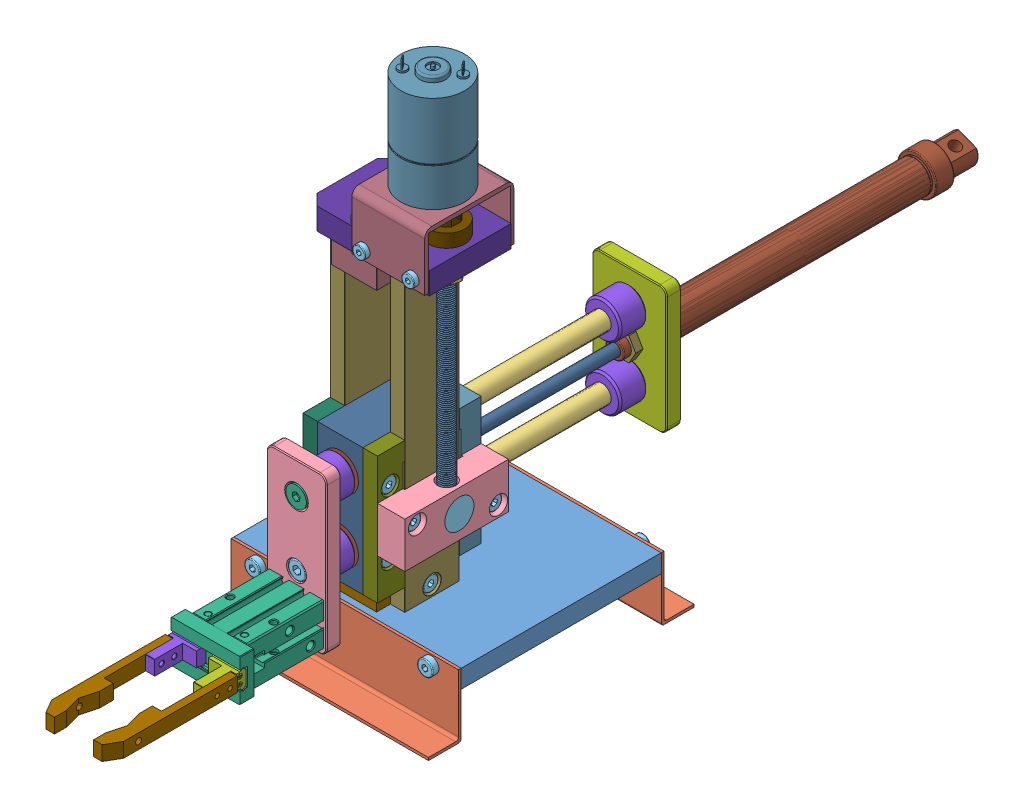
SolidWorks assembly cum_s4, configuration Default. Lengths in mm.
Overall size (125 291 489.3).
72 component instances, 34 part files, 168 mates.
Components (placement in the parent):
- tam_de-1: tam_de [Default] at (55.7373 162.4347 98.3877) size (125 10 110)
- khoi_do-1: khoi_do [Default] at (118.2373 137.4347 153.3877) x (0 0 1) z (0 -1 0) size (18 125 35)
- khoi_do-2: khoi_do [Default] at (-6.7627 137.4347 43.3877) x (0 0 -1) z (0 -1 0) size (18 125 35)
- chot_dan_huong-1: chot_dan_huong [Default] at (55.7373 236.9347 173.4357) x (0.807467 -0.589913 0) z (0.589913 0.807467 0) size (10 175 10)
- chot_dan_huong-2: chot_dan_huong [Default] at (55.7373 201.9347 173.4357) x (0.458763 0.888559 0) z (-0.888559 0.458763 0) size (10 175 10)
- ban_canh_truoc-1: ban_canh_truoc [Default] at (55.7373 211.4347 173.4357) x (1 0 0) z (0 -1 0) size (33 8 86)
- socket head thin cap screw_din-14: socket head thin cap screw_din [DIN 7984 - M5 x 8 --- 5.6N] at (8.2373 167.4347 38.3877) x (0 0 1) z (-1 0 0) size (11.5 8.5 8.5)
- socket head thin cap screw_din-16: socket head thin cap screw_din [DIN 7984 - M5 x 8 --- 5.6N] at (8.2373 167.4347 158.3877) x (0 0 -1) z (1 0 0) size (11.5 8.5 8.5)
- socket head thin cap screw_din-17: socket head thin cap screw_din [DIN 7984 - M5 x 8 --- 5.6N] at (103.2373 167.4347 158.3877) x (0 0 -1) z (1 0 0) size (11.5 8.5 8.5)
- socket head thin cap screw_din-18: socket head thin cap screw_din [DIN 7984 - M5 x 8 --- 5.6N] at (63.2373 164.6347 109.3877) x (0 1 0) z (0 0 1) size (11.5 8.5 8.5)
- socket head thin cap screw_din-19: socket head thin cap screw_din [DIN 7984 - M5 x 8 --- 5.6N] at (48.2373 164.6347 145.3877) x (0 1 0) z (0 0 1) size (11.5 8.5 8.5)
- socket head thin cap screw_din-22: socket head thin cap screw_din [DIN 7984 - M5 x 8 --- 5.6N] at (103.2373 167.4347 38.3877) x (0 0 1) z (-1 0 0) size (11.5 8.5 8.5)
- socket head thin cap screw_din-23: socket head thin cap screw_din [DIN 7984 - M6 x 10 --- 7N] at (55.7373 201.9347 -9.3643) x (0 0 1) z (-1 0 0) size (14 10 10)
- socket head thin cap screw_din-24: socket head thin cap screw_din [DIN 7984 - M6 x 10 --- 7N] at (55.7373 201.6984 181.2357) x (0 0 -1) z (1 0 0) size (14 10 10)
- socket csink head cap screw 10642_din-2: socket csink head cap screw 10642_din [EN ISO 10642 - M6 x 8 - 8N] at (55.7373 236.9347 -9.7843) x (0 0 1) z (-0.997818 -0.066017 0) size (8 11.34 11.34)
- socket csink head cap screw 10642_din-3: socket csink head cap screw 10642_din [EN ISO 10642 - M6 x 8 - 8N] at (55.7373 236.9347 181.6557) x (0 0 -1) z (0.99607 -0.088565 0) size (8 11.34 11.34)
- s3_ban_canh_sau-1: s3_ban_canh_sau [Default] at (55.7373 219.4347 -1.5643) x (-1 0 0) z (0 -1 0) size (41 8 70)
- bac_chan-1: bac_chan [Default] at (55.7373 236.9347 158.4357) x (-0.999622 -0.027501 0) z (-0.027501 0.999622 0) size (20 15 20)
- bac_chan-2: bac_chan [Default] at (55.7373 201.9347 158.4357) x (1 0 0) z (0 -1 0) size (20 15 20)
- bac_chan-3: bac_chan [Default] at (55.7373 236.9347 13.4357) x (-0.997429 -0.071658 0) z (0.071658 -0.997429 0) size (20 15 20)
- bac_chan-4: bac_chan [Default] at (55.7373 201.9347 13.4357) x (1 0 0) z (0 1 0) size (20 15 20)
- mieng_dem_duoi-1: mieng_dem_duoi [Default] at (55.7373 172.4347 127.3877) size (25 12 45)
- con_truot_s4_as-1: con_truot_s4_as [Default] at (19.8229 164.1862 110.8419) x (0 0 1) z (0 1 0) size (45 28.02 70)
  - con_truot_s4-1: con_truot_s4 [Default] at (24.0458 23.4144 55.2485) size (45 25 70)
  - bat_lot-1: bat_lot [Default] at (46.5458 35.9144 72.7485) x (0 0.967524 -0.252781) z (0 0.252781 0.967524) size (20 10 20)
  - bat_lot-2: bat_lot [Default] at (46.5458 35.9144 37.7485) x (0 0.967524 -0.252781) z (0 0.252781 0.967524) size (20 10 20)
  - bat_lot-3: bat_lot [Default] at (1.5458 35.9144 72.7485) x (0 0.603074 -0.797685) z (0 -0.797685 -0.603074) size (20 10 20)
  - bat_lot-4: bat_lot [Default] at (1.5458 35.9144 37.7485) x (0 0.603074 -0.797685) z (0 -0.797685 -0.603074) size (20 10 20)
- thanh_dan_huong_lon-1: thanh_dan_huong_lon [Default] at (68.2373 254.9347 127.3877) x (0 0 -1) z (0 -1 0) size (30 8 165)
- thanh_dan_huong_lon-2: thanh_dan_huong_lon [Default] at (43.2373 254.9347 127.3877) x (0 0 -1) z (0 1 0) size (30 8 165)
- mieng_dem_tren-1: mieng_dem_tren [Default] at (55.7373 325.4347 127.3877) size (25 12 45)
- tam_dan_huong-1: tam_dan_huong [Default] at (35.2373 219.4347 106.3877) x (0 0 -1) z (0 -1 0) size (12 41 70)
- thanh_dan_huong_nho_1-1: thanh_dan_huong_nho_1 [Default] at (43.2373 219.4347 149.8877) x (0 0 -1) z (0 1 0) size (15 8 70)
- thanh_dan_huong_nho_2-1: thanh_dan_huong_nho_2 [Default] at (68.2373 219.4347 149.8877) x (0 0 -1) z (0 -1 0) size (15 8 70)
- tam_de_s5-1: tam_de_s5 [Default] at (63.3484 349.4347 127.3877) x (0 0 1) z (1 0 0) size (45 12 67.78)
- dau_kep_truc_vit-1: dau_kep_truc_vit [Default] at (84.2373 339.6347 127.3877) x (-0.999219 0 -0.039516) z (0.039516 0 -0.999219) size (20 25 20)
- truc_truyen_dong-1: truc_truyen_dong [Default] at (84.2373 208.6347 127.3877) x (-0.676321 0 -0.736607) z (0.736607 0 -0.676321) size (8.27 150.4 9.24)
- vong_dem-1: vong_dem [Default] at (84.2373 337.4347 127.3877) x (-0.77791 0 0.628376) z (-0.628376 0 -0.77791) size (19.6 2 19.6)
- hex nut gradec_din-5: hex nut gradec_din [Hexagon Nut ISO 4034 - M8 - N] at (84.2373 329.5347 127.3877) x (0.78301 0 -0.622008) z (0 -1 0) size (13 15.01 7.9)
- thanh_ngang-1: thanh_ngang [Default] at (83.7373 206.9347 128.8877) x (0 0 -1) z (1 0 0) size (57 25 15)
- dai_oc-1: dai_oc [Default] at (77.2373 219.4347 127.3877) x (0 0.924256 0.381773) z (0 0.381773 -0.924256) size (16 14 16)
- socket head thin cap screw_din-25: socket head thin cap screw_din [DIN 7984 - M5 x 8 --- 5.6N] at (89.0373 212.9347 105.8877) x (-1 0 0) z (0 0.924225 0.381849) size (11.5 8.5 8.5)
- socket head thin cap screw_din-26: socket head thin cap screw_din [DIN 7984 - M5 x 8 --- 5.6N] at (89.0373 225.9347 150.3877) x (-1 0 0) z (0 0.924225 0.381849) size (11.5 8.5 8.5)
- socket head thin cap screw_din-27: socket head thin cap screw_din [DIN 7984 - M5 x 8 --- 5.6N] at (75.5373 236.9347 150.3877) x (-1 0 0) z (0 0.924225 0.381849) size (11.5 8.5 8.5)
- socket head thin cap screw_din-28: socket head thin cap screw_din [DIN 7984 - M5 x 8 --- 5.6N] at (75.5373 201.9347 150.3877) x (-1 0 0) z (0 0.924225 0.381849) size (11.5 8.5 8.5)
- socket head thin cap screw_din-29: socket head thin cap screw_din [DIN 7984 - M5 x 8 --- 5.6N] at (75.5373 178.4347 127.3877) x (-1 0 0) z (0 0.924225 0.381849) size (11.5 8.5 8.5)
- socket head thin cap screw_din-30: socket head thin cap screw_din [DIN 7984 - M5 x 8 --- 5.6N] at (35.9373 178.4347 127.3877) size (11.5 8.5 8.5)
- socket head thin cap screw_din-31: socket head thin cap screw_din [DIN 7984 - M5 x 8 --- 5.6N] at (35.9373 201.9347 150.3877) size (11.5 8.5 8.5)
- socket head thin cap screw_din-32: socket head thin cap screw_din [DIN 7984 - M5 x 8 --- 5.6N] at (35.9373 236.9347 150.3877) size (11.5 8.5 8.5)
- socket head thin cap screw_din-33: socket head thin cap screw_din [DIN 7984 - M5 x 8 --- 5.6N] at (35.9373 331.4347 127.3877) size (11.5 8.5 8.5)
- socket head thin cap screw_din-34: socket head thin cap screw_din [DIN 7984 - M5 x 8 --- 5.6N] at (63.2373 248.4347 102.5877) x (0 0 1) z (-1 0 0) size (11.5 8.5 8.5)
- socket head thin cap screw_din-35: socket head thin cap screw_din [DIN 7984 - M5 x 8 --- 5.6N] at (48.2373 190.4347 102.5877) x (0 0 1) z (-1 0 0) size (11.5 8.5 8.5)
- socket head thin cap screw_din-36: socket head thin cap screw_din [DIN 7984 - M5 x 8 --- 5.6N] at (55.7373 352.9347 145.3877) x (0 -1 0) z (0 0 1) size (11.5 8.5 8.5)
- socket head thin cap screw_din-37: socket head thin cap screw_din [DIN 7984 - M5 x 8 --- 5.6N] at (55.7373 352.9347 109.3877) x (0 -1 0) z (0 0 1) size (11.5 8.5 8.5)
- body-2: body [默认] at (55.7373 183.6347 181.4357) x (0 0 -1) z (0 1 0) size (50 38 23.6)
- ljaw-1: ljaw [默认] at (59.0373 183.6347 181.4357) x (0 0 -1) z (0 -1 0) size (21.3 15.4 11.12)
- rjaw-1: rjaw [默认] at (52.4373 183.6347 181.4357) x (0 0 -1) z (0 -1 0) size (21.3 15.6 11.12)
- jaw - ip-1: jaw - ip [Default] at (36.1895 179.6347 269.1328) x (0 0 -1) z (1 0 0) size (70 8 9.03)
- jaw - ip-2: jaw - ip [Default] at (75.2851 187.6347 269.1328) x (0 0 -1) z (-1 0 0) size (70 8 9.03)
- Part1-1: Part1 [Default] at (55.7373 219.4347 -37.6123) x (-0.66535 -0.746532 0) z (-0.746532 0.66535 0) size (6.2 165 6.2)
- 16 X 100 Cylinder bore-1: 16 X 100 Cylinder bore [Default] at (55.7373 219.4347 -89.5643) x (-0.367131 -0.930169 0) z (0 0 -1) size (21.5 21.5 192)
- hex thin nut gradeb_din-1: hex thin nut gradeb_din [Hexagon Nut ISO 4036 - M8 - N] at (55.7373 219.4347 2.4357) x (0.866025 0.5 0) z (0 0 1) size (13 15.01 4)
- de dong co-1: de dong co [Default] at (96.7373 353.9347 127.4836) x (0 0 1) z (0 -1 0) size (49 40 31)
- moto-1: moto [Default] at (76.7373 371.6519 127.4836) x (0 -1 0) z (-1 0 0) size (63.5 35 35)
- link-1: link [Default] at (76.7432 371.6519 127.1872) x (0 -1 0) z (-0.999219 0 -0.039516) size (19 10 10)
- socket head thin cap screw_din-39: socket head thin cap screw_din [DIN 7984 - M4 x 6 --- 3.9N] at (63.2373 343.4347 154.7836) x (0 0 -1) z (1 0 0) size (8.8 7 7)
- socket head thin cap screw_din-40: socket head thin cap screw_din [DIN 7984 - M4 x 6 --- 3.9N] at (90.2373 343.4347 100.1836) x (0 0 1) z (-1 0 0) size (8.8 7 7)
- socket head thin cap screw_din-41: socket head thin cap screw_din [DIN 7984 - M4 x 6 --- 3.9N] at (63.2373 343.4347 100.1836) x (0 0 1) z (-1 0 0) size (8.8 7 7)
- socket head thin cap screw_din-44: socket head thin cap screw_din [DIN 7984 - M4 x 6 --- 3.9N] at (90.2373 343.4347 154.7836) x (0 0 -1) z (1 0 0) size (8.8 7 7)
- slotted headless screw_din-5: slotted headless screw_din [DIN 427 M2 x 5 --- 2.4N] at (91.7315 361.1868 127.6841) x (-0.999219 0 -0.039516) z (0.039508 -0.021253 -0.998993) size (5 2 2)
- socket head thin cap screw_din-45: socket head thin cap screw_din [DIN 7984 - M4 x 10 --- 7.9N] at (66.7373 191.1347 175.0357) x (0 0 1) z (-1 0 0) size (12.8 7 7)
- socket head thin cap screw_din-46: socket head thin cap screw_din [DIN 7984 - M4 x 10 --- 7.9N] at (44.7373 176.1347 175.0357) x (0 0 1) z (-1 0 0) size (12.8 7 7)
Mates (geometry in assembly coordinates):
- Parallel1: parallel aligned: plane of tam_de-1 through (-6.7627 172.4347 153.3877) normal (0 0 1); plane of khoi_do-1 through (-6.7627 172.4347 154.8877) normal (0 0 1)
- Concentric1: concentric aligned: cylinder of tam_de-1 through (8.2373 167.4347 153.3877) axis (0 0 1) radius 2.1; circle of khoi_do-1
- Concentric2: concentric aligned: circle of tam_de-1; circle of khoi_do-1
- Coincident1: coincident anti-aligned: plane of tam_de-1 through (-6.7627 172.4347 153.3877) normal (0 0 1); plane of khoi_do-1 through (-6.7627 137.4347 153.3877) normal (0 0 -1)
- Parallel2: parallel anti-aligned: plane of tam_de-1 through (-6.7627 172.4347 43.3877) normal (0 0 -1); plane of khoi_do-2 through (118.2373 137.4347 43.3877) normal (0 0 1)
- Concentric3: concentric aligned: circle of tam_de-1; cylinder of khoi_do-2 through (8.2373 167.4347 43.3877) axis (0 0 -1) radius 2.75
- Parallel3: parallel aligned: plane of tam_de-1 through (55.7373 172.4347 98.3877) normal (0 1 0); plane of khoi_do-2 through (118.2373 172.4347 43.3877) normal (0 1 0)
- Coincident2: coincident anti-aligned: plane of tam_de-1 through (-6.7627 172.4347 43.3877) normal (0 0 -1); plane of khoi_do-2 through (118.2373 137.4347 43.3877) normal (0 0 1)
- Concentric18: concentric aligned: cylinder of chot_dan_huong-2 through (55.7373 272.9347 260.3877) axis (0 0 1) radius 2.5; circle of ban_canh_truoc-1
- Concentric19: concentric anti-aligned: circle of chot_dan_huong-1; circle of ban_canh_truoc-1
- Coincident14: coincident aligned: plane of chot_dan_huong-1 through (55.7373 307.9347 260.3877) normal (0 0 1); circle of ban_canh_truoc-1
- Coincident15: coincident aligned: circle of chot_dan_huong-2; plane of ban_canh_truoc-1 through (55.7373 282.4347 260.3877) normal (0 0 -1)
- Concentric37: concentric aligned: cylinder of khoi_do-2 through (8.2373 167.4347 43.3877) axis (0 0 -1) radius 2.75; cylinder of socket head thin cap screw_din-14 through (8.2373 167.4347 6.6377) axis (0 0 -1) radius 4.25
- Coincident28: coincident anti-aligned: plane of khoi_do-2 through (118.2373 172.4347 41.8877) normal (0 0 -1); plane of socket head thin cap screw_din-14 through (8.2373 171.6847 41.8877) normal (0 0 1)
- Concentric39: concentric aligned: cylinder of khoi_do-1 through (8.2373 167.4347 153.3877) axis (0 0 1) radius 2.75; cylinder of socket head thin cap screw_din-16 through (8.2373 167.4347 190.1377) axis (0 0 1) radius 4.25
- Coincident30: coincident anti-aligned: plane of khoi_do-1 through (-6.7627 172.4347 154.8877) normal (0 0 1); plane of socket head thin cap screw_din-16 through (8.2373 171.6847 154.8877) normal (0 0 -1)
- Concentric40: concentric aligned: cylinder of khoi_do-1 through (103.2373 167.4347 153.3877) axis (0 0 1) radius 2.75; cylinder of socket head thin cap screw_din-17 through (103.2373 167.4347 190.1377) axis (0 0 1) radius 4.25
- Coincident31: coincident anti-aligned: plane of khoi_do-1 through (-6.7627 172.4347 154.8877) normal (0 0 1); plane of socket head thin cap screw_din-17 through (103.2373 171.6847 154.8877) normal (0 0 -1)
- Concentric41: concentric aligned: cylinder of tam_de-1 through (63.2373 172.4347 109.3877) axis (0 -1 0) radius 2.75; cylinder of socket head thin cap screw_din-18 through (63.2373 132.8847 109.3877) axis (0 -1 0) radius 4.25
- Coincident32: coincident anti-aligned: plane of tam_de-1 through (63.2373 168.1347 109.3877) normal (0 -1 0); plane of socket head thin cap screw_din-18 through (58.9873 168.1347 109.3877) normal (0 1 0)
- Concentric42: concentric aligned: cylinder of tam_de-1 through (48.2373 172.4347 145.3877) axis (0 -1 0) radius 2.75; cylinder of socket head thin cap screw_din-19 through (48.2373 132.8847 145.3877) axis (0 -1 0) radius 4.25
- Coincident33: coincident anti-aligned: plane of tam_de-1 through (48.2373 168.1347 145.3877) normal (0 -1 0); plane of socket head thin cap screw_din-19 through (43.9873 168.1347 145.3877) normal (0 1 0)
- Concentric451: concentric aligned: cylinder of khoi_do-2 through (103.2373 167.4347 43.3877) axis (0 0 -1) radius 2.75; cylinder of socket head thin cap screw_din-22 through (103.2373 167.4347 6.6377) axis (0 0 -1) radius 4.25
- Coincident361: coincident anti-aligned: plane of khoi_do-2 through (118.2373 172.4347 41.8877) normal (0 0 -1); plane of socket head thin cap screw_din-22 through (103.2373 171.6847 41.8877) normal (0 0 1)
- Concentric47: concentric aligned: cylinder of ban_canh_truoc-1 through (55.7373 272.6984 264.1877) axis (0 0 1) radius 5.5; cylinder of socket head thin cap screw_din-24 through (55.7373 272.6984 299.9377) axis (0 0 1) radius 5
- Coincident38: coincident anti-aligned: plane of ban_canh_truoc-1 through (55.7373 272.6984 264.1877) normal (0 0 1); plane of socket head thin cap screw_din-24 through (55.7373 277.6984 264.1877) normal (0 0 -1)
- Coincident40: coincident aligned: cone of ban_canh_truoc-1 through (55.7373 236.9347 177.8321) axis (0 0 -1); cylinder of socket csink head cap screw 10642_din-3 through (55.7373 236.9347 180.2021) axis (0 0 -1) radius 785.3982
- Concentric452: concentric aligned: circle of chot_dan_huong-2; circle of s3_ban_canh_sau-1
- Coincident362: coincident anti-aligned: plane of chot_dan_huong-1 through (55.7373 307.9347 85.3877) normal (0 0 -1); plane of s3_ban_canh_sau-1 through (55.7373 290.4347 85.3877) normal (0 0 1)
- Concentric453: concentric anti-aligned: cylinder of socket csink head cap screw 10642_din-2 through (55.7373 307.9347 77.1677) axis (0 0 -1) radius 3; cylinder of s3_ban_canh_sau-1 through (55.7373 307.9347 77.3877) axis (0 0 1) radius 3.3
- Coincident363: coincident aligned: cylinder of socket csink head cap screw 10642_din-2 through (55.7373 236.9347 -2.404) axis (0 0 1) radius 785.3982; cylinder of s3_ban_canh_sau-1 through (55.7373 236.9347 -0.034) axis (0 0 1) radius 785.3982
- Concentric454: concentric aligned: cylinder of chot_dan_huong-2 through (55.7373 272.9347 85.3877) axis (0 0 -1) radius 2.5; cylinder of socket head thin cap screw_din-23 through (55.7373 272.9347 45.8377) axis (0 0 -1) radius 3
- Coincident364: coincident anti-aligned: plane of socket head thin cap screw_din-23 through (55.7373 277.9347 81.5877) normal (0 0 1); plane of s3_ban_canh_sau-1 through (55.7373 272.9347 81.5877) normal (0 0 -1)
- Concentric456: concentric anti-aligned: cylinder of chot_dan_huong-1 through (55.7373 307.9347 85.3877) axis (0 0 1) radius 5; cylinder of bac_chan-1 through (55.7373 307.9347 260.3877) axis (0 0 -1) radius 5
- Coincident366: coincident anti-aligned: plane of ban_canh_truoc-1 through (55.7373 282.4347 260.3877) normal (0 0 -1); plane of bac_chan-1 through (55.7373 307.9347 260.3877) normal (0 0 1)
- Concentric457: concentric anti-aligned: cylinder of chot_dan_huong-2 through (55.7373 272.9347 85.3877) axis (0 0 1) radius 5; circle of bac_chan-2
- Coincident367: coincident anti-aligned: plane of ban_canh_truoc-1 through (55.7373 282.4347 260.3877) normal (0 0 -1); plane of bac_chan-2 through (55.7373 272.9347 260.3877) normal (0 0 1)
- Concentric458: concentric anti-aligned: cylinder of chot_dan_huong-1 through (55.7373 307.9347 85.3877) axis (0 0 1) radius 5; circle of bac_chan-3
- Coincident368: coincident anti-aligned: plane of s3_ban_canh_sau-1 through (55.7373 290.4347 85.3877) normal (0 0 1); plane of bac_chan-3 through (55.7373 307.9347 85.3877) normal (0 0 -1)
- Concentric459: concentric anti-aligned: cylinder of chot_dan_huong-2 through (55.7373 272.9347 85.3877) axis (0 0 1) radius 5; circle of bac_chan-4
- Coincident369: coincident anti-aligned: plane of s3_ban_canh_sau-1 through (55.7373 290.4347 85.3877) normal (0 0 1); plane of bac_chan-4 through (55.7373 272.9347 85.3877) normal (0 0 -1)
- Concentric460: concentric anti-aligned: cylinder of socket head thin cap screw_din-19 through (48.2373 132.8847 145.3877) axis (0 -1 0) radius 2.5; cylinder of mieng_dem_duoi-1 through (48.2373 184.4347 145.3877) axis (0 1 0) radius 2.1
- Concentric461: concentric anti-aligned: cylinder of socket head thin cap screw_din-18 through (63.2373 132.8847 109.3877) axis (0 -1 0) radius 2.5; cylinder of mieng_dem_duoi-1 through (63.2373 184.4347 109.3877) axis (0 1 0) radius 2.1
- Coincident371: coincident anti-aligned: plane of tam_de-1 through (55.7373 172.4347 98.3877) normal (0 1 0); plane of mieng_dem_duoi-1 through (55.7373 172.4347 127.3877) normal (0 -1 0)
- Parallel6: parallel anti-aligned: plane of mieng_dem_duoi-1 through (55.7373 184.4347 127.3877) normal (0 1 0); plane of con_truot_s4_as-1/con_truot_s4-1 through (226.6799 255.4347 112.3877) normal (0 -1 0)
- Parallel7: parallel aligned: plane of mieng_dem_duoi-1 through (68.2373 184.4347 149.8877) normal (1 0 0); plane of con_truot_s4_as-1/con_truot_s4-1 through (68.2373 290.4347 134.8877) normal (1 0 0)
- Coincident372: coincident aligned: plane of mieng_dem_duoi-1 through (68.2373 184.4347 149.8877) normal (1 0 0); plane of con_truot_s4_as-1/con_truot_s4-1 through (68.2373 290.4347 134.8877) normal (1 0 0)
- Concentric464: concentric aligned: cylinder of chot_dan_huong-2 through (55.7373 272.9347 85.3877) axis (0 0 1) radius 5; cylinder of con_truot_s4_as-1/bat_lot-2 through (55.7373 272.9347 147.3877) axis (0 0 1) radius 5
- Concentric465: concentric aligned: cylinder of chot_dan_huong-1 through (55.7373 307.9347 85.3877) axis (0 0 1) radius 5; circle of con_truot_s4_as-1/con_truot_s4-1
- Parallel9: parallel aligned: plane of con_truot_s4_as-1/con_truot_s4-1 through (68.2373 290.4347 134.8877) normal (1 0 0); plane of thanh_dan_huong_lon-1 through (76.2373 254.9347 127.3877) normal (1 0 0)
- Concentric466: concentric anti-aligned: circle of mieng_dem_duoi-1; circle of thanh_dan_huong_lon-1
- Parallel10: parallel aligned: plane of con_truot_s4_as-1/con_truot_s4-1 through (68.2373 341.4347 112.3877) normal (0 0 -1); plane of thanh_dan_huong_lon-1 through (76.2373 172.4347 112.3877) normal (0 0 -1)
- Coincident374: coincident anti-aligned: plane of mieng_dem_duoi-1 through (68.2373 184.4347 149.8877) normal (1 0 0); plane of thanh_dan_huong_lon-1 through (68.2373 254.9347 127.3877) normal (-1 0 0)
- Parallel11: parallel: line of thanh_dan_huong_lon-1 through (68.2373 337.3347 112.4877) axis (0 -1 0); plane of thanh_dan_huong_lon-2 through (35.2373 337.4347 142.3877) normal (0 0 1)
- Parallel12: parallel aligned: plane of thanh_dan_huong_lon-1 through (68.2373 254.9347 127.3877) normal (-1 0 0); plane of thanh_dan_huong_lon-2 through (35.2373 254.9347 127.3877) normal (-1 0 0)
- Concentric467: concentric anti-aligned: cylinder of mieng_dem_duoi-1 through (68.2373 178.4347 127.3877) axis (1 0 0) radius 2.1; circle of thanh_dan_huong_lon-2
- Coincident375: coincident anti-aligned: plane of mieng_dem_duoi-1 through (43.2373 184.4347 149.8877) normal (-1 0 0); plane of thanh_dan_huong_lon-2 through (43.2373 254.9347 127.3877) normal (1 0 0)
- Concentric468: concentric aligned: cylinder of thanh_dan_huong_lon-2 through (39.4373 331.4347 127.3877) axis (-1 0 0) radius 5; cylinder of mieng_dem_tren-1 through (43.2373 331.4347 127.3877) axis (-1 0 0) radius 2.1
- Parallel13: parallel aligned: plane of mieng_dem_duoi-1 through (55.7373 184.4347 127.3877) normal (0 1 0); plane of mieng_dem_tren-1 through (55.7373 337.4347 127.3877) normal (0 1 0)
- Coincident376: coincident anti-aligned: plane of thanh_dan_huong_lon-2 through (43.2373 254.9347 127.3877) normal (1 0 0); plane of mieng_dem_tren-1 through (43.2373 337.4347 149.8877) normal (-1 0 0)
- Parallel14: parallel anti-aligned: plane of con_truot_s4_as-1/con_truot_s4-1 through (68.2373 341.4347 112.3877) normal (0 0 -1); plane of tam_dan_huong-1 through (76.2373 315.4347 111.3877) normal (0 0 1)
- Parallel15: parallel anti-aligned: plane of con_truot_s4_as-1/con_truot_s4-1 through (193.5245 325.4347 112.3877) normal (0 1 0); plane of tam_dan_huong-1 through (76.2373 255.4347 112.3877) normal (0 -1 0)
- Concentric469: concentric aligned: circle of con_truot_s4_as-1/con_truot_s4-1; circle of tam_dan_huong-1
- Coincident377: coincident anti-aligned: plane of con_truot_s4_as-1/con_truot_s4-1 through (68.2373 341.4347 112.3877) normal (0 0 -1); plane of tam_dan_huong-1 through (76.2373 315.4347 112.3877) normal (0 0 1)
- Concentric470: concentric anti-aligned: circle of con_truot_s4_as-1/con_truot_s4-1; circle of thanh_dan_huong_nho_1-1
- Concentric474: concentric anti-aligned: cylinder of con_truot_s4_as-1/con_truot_s4-1 through (68.2373 272.9347 150.3877) axis (1 0 0) radius 2.1; cylinder of thanh_dan_huong_nho_1-1 through (39.4373 272.9347 150.3877) axis (-1 0 0) radius 5
- Coincident378: coincident anti-aligned: plane of con_truot_s4_as-1/con_truot_s4-1 through (43.2373 290.4347 134.8877) normal (-1 0 0); plane of thanh_dan_huong_nho_1-1 through (43.2373 290.4347 149.8877) normal (1 0 0)
- Coincident379: coincident anti-aligned: plane of thanh_dan_huong_lon-2 through (35.2373 337.4347 112.3877) normal (0 0 -1); plane of tam_dan_huong-1 through (76.2373 315.4347 112.3877) normal (0 0 1)
- Concentric475: concentric anti-aligned: circle of con_truot_s4_as-1/con_truot_s4-1; circle of thanh_dan_huong_nho_2-1
- Concentric476: concentric anti-aligned: circle of con_truot_s4_as-1/con_truot_s4-1; circle of thanh_dan_huong_nho_2-1
- Coincident380: coincident anti-aligned: plane of con_truot_s4_as-1/con_truot_s4-1 through (68.2373 290.4347 134.8877) normal (1 0 0); plane of thanh_dan_huong_nho_2-1 through (68.2373 290.4347 149.8877) normal (-1 0 0)
- Coincident381: coincident anti-aligned: plane of s3_ban_canh_sau-1 through (55.7373 290.4347 85.3877) normal (0 0 1); plane of bac_chan-3 through (55.7373 307.9347 85.3877) normal (0 0 -1)
- Concentric477: concentric aligned: circle of s3_ban_canh_sau-1; circle of bac_chan-3
- LimitDistance5: limit distance = 0 mm anti-aligned: plane of con_truot_s4_as-1/con_truot_s4-1 through (226.6799 184.4347 112.3877) normal (0 -1 0); plane of mieng_dem_duoi-1 through (55.7373 184.4347 127.3877) normal (0 1 0)
- Parallel16: parallel anti-aligned: plane of mieng_dem_tren-1 through (55.7373 337.4347 127.3877) normal (0 1 0); plane of tam_de_s5-1 through (63.3484 337.4347 127.3877) normal (0 -1 0)
- Parallel17: parallel anti-aligned: plane of thanh_dan_huong_lon-1 through (76.2373 254.9347 127.3877) normal (1 0 0); plane of tam_de_s5-1 through (29.4595 337.4347 110.8877) normal (-1 0 0)
- Concentric478: concentric anti-aligned: cylinder of tam_de_s5-1 through (84.2373 337.4347 127.3877) axis (0 1 0) radius 7; cylinder of dau_kep_truc_vit-1 through (84.2373 349.4347 127.3877) axis (0 -1 0) radius 7
- Coincident382: coincident anti-aligned: plane of tam_de_s5-1 through (63.3484 349.4347 127.3877) normal (0 1 0); plane of dau_kep_truc_vit-1 through (84.2373 349.4347 127.3877) normal (0 -1 0)
- Concentric479: concentric aligned: cylinder of mieng_dem_tren-1 through (55.7373 337.4347 145.3877) axis (0 1 0) radius 2.1; cylinder of tam_de_s5-1 through (55.7373 337.4347 145.3877) axis (0 1 0) radius 2.75
- Coincident383: coincident anti-aligned: plane of mieng_dem_tren-1 through (55.7373 337.4347 127.3877) normal (0 1 0); plane of tam_de_s5-1 through (63.3484 337.4347 127.3877) normal (0 -1 0)
- Concentric480: concentric anti-aligned: cylinder of dau_kep_truc_vit-1 through (84.2373 339.6347 127.3877) axis (0 -1 0) radius 3.4; circle of truc_truyen_dong-1
- Coincident384: coincident anti-aligned: plane of dau_kep_truc_vit-1 through (84.2373 356.6347 127.3877) normal (0 -1 0); plane of truc_truyen_dong-1 through (84.2373 356.6347 127.3877) normal (0 1 0)
- Concentric481: concentric aligned: cylinder of tam_de_s5-1 through (84.2373 339.9347 127.3877) axis (0 -1 0) radius 10; cylinder of vong_dem-1 through (84.2373 339.4347 127.3877) axis (0 -1 0) radius 9.8
- Coincident385: coincident aligned: plane of tam_de_s5-1 through (63.3484 337.4347 127.3877) normal (0 -1 0); plane of vong_dem-1 through (84.2373 337.4347 127.3877) normal (0 -1 0)
- Concentric484: concentric aligned: cylinder of vong_dem-1 through (84.2373 339.4347 127.3877) axis (0 -1 0) radius 4.25; cylinder of hex nut gradec_din-5 through (84.2373 354.5722 127.3877) axis (0 -1 0) radius 4
- Coincident387: coincident anti-aligned: plane of vong_dem-1 through (84.2373 337.4347 127.3877) normal (0 -1 0); plane of hex nut gradec_din-5 through (88.9058 337.4347 133.2647) normal (0 1 0)
- Lock1: lock: unknown of dau_kep_truc_vit-1; unknown of vong_dem-1
- Lock2: lock: unknown of vong_dem-1; unknown of hex nut gradec_din-5
- Lock3: lock: unknown of truc_truyen_dong-1; unknown of hex nut gradec_din-5
- Parallel18: parallel aligned: plane of thanh_dan_huong_lon-1 through (76.2373 254.9347 127.3877) normal (1 0 0); plane of thanh_ngang-1 through (91.2373 302.9347 157.3877) normal (1 0 0)
- Parallel19: parallel aligned: plane of thanh_dan_huong_nho_2-1 through (76.2373 255.4347 157.3877) normal (0 0 1); plane of thanh_ngang-1 through (91.2373 302.9347 157.3877) normal (0 0 1)
- Concentric485: concentric aligned: cylinder of thanh_dan_huong_nho_2-1 through (76.2373 296.9347 150.3877) axis (1 0 0) radius 2.1; cylinder of thanh_ngang-1 through (76.2373 296.9347 150.3877) axis (1 0 0) radius 2.75
- Coincident388: coincident anti-aligned: plane of thanh_dan_huong_nho_2-1 through (76.2373 290.4347 149.8877) normal (1 0 0); plane of thanh_ngang-1 through (76.2373 302.9347 157.3877) normal (-1 0 0)
- Concentric486: concentric anti-aligned: circle of truc_truyen_dong-1; cylinder of dai_oc-1 through (84.2373 298.4347 127.3877) axis (0 1 0) radius 3.4
- Concentric487: concentric aligned: circle of thanh_ngang-1; circle of dai_oc-1
- Concentric488: concentric aligned: cylinder of thanh_ngang-1 through (76.2373 283.9347 105.8877) axis (1 0 0) radius 2.75; cylinder of socket head thin cap screw_din-25 through (120.7873 283.9347 105.8877) axis (1 0 0) radius 4.25
- Coincident389: coincident anti-aligned: plane of thanh_ngang-1 through (85.5373 283.9347 105.8877) normal (1 0 0); plane of socket head thin cap screw_din-25 through (85.5373 282.3118 109.8157) normal (-1 0 0)
- Concentric489: concentric aligned: cylinder of thanh_ngang-1 through (76.2373 296.9347 150.3877) axis (1 0 0) radius 2.75; cylinder of socket head thin cap screw_din-26 through (120.7873 296.9347 150.3877) axis (1 0 0) radius 4.25
- Coincident390: coincident anti-aligned: plane of thanh_ngang-1 through (85.5373 296.9347 150.3877) normal (1 0 0); plane of socket head thin cap screw_din-26 through (85.5373 295.3118 154.3157) normal (-1 0 0)
- Concentric490: concentric aligned: cylinder of thanh_dan_huong_nho_2-1 through (72.0373 307.9347 150.3877) axis (1 0 0) radius 5; cylinder of socket head thin cap screw_din-27 through (107.2873 307.9347 150.3877) axis (1 0 0) radius 4.25
- Coincident391: coincident anti-aligned: plane of thanh_dan_huong_nho_2-1 through (72.0373 307.9347 150.3877) normal (1 0 0); plane of socket head thin cap screw_din-27 through (72.0373 306.3118 154.3157) normal (-1 0 0)
- Concentric491: concentric aligned: cylinder of thanh_dan_huong_nho_2-1 through (72.0373 272.9347 150.3877) axis (1 0 0) radius 5; cylinder of socket head thin cap screw_din-28 through (107.2873 272.9347 150.3877) axis (1 0 0) radius 4.25
- Coincident392: coincident anti-aligned: plane of thanh_dan_huong_nho_2-1 through (72.0373 272.9347 150.3877) normal (1 0 0); plane of socket head thin cap screw_din-28 through (72.0373 271.3118 154.3157) normal (-1 0 0)
- Concentric492: concentric aligned: cylinder of thanh_dan_huong_lon-1 through (72.0373 178.4347 127.3877) axis (1 0 0) radius 5; cylinder of socket head thin cap screw_din-29 through (107.2873 178.4347 127.3877) axis (1 0 0) radius 4.25
- Coincident393: coincident anti-aligned: plane of thanh_dan_huong_lon-1 through (72.0373 178.4347 127.3877) normal (1 0 0); plane of socket head thin cap screw_din-29 through (72.0373 176.8118 131.3157) normal (-1 0 0)
- Concentric493: concentric anti-aligned: cylinder of thanh_dan_huong_lon-2 through (35.2373 178.4347 127.3877) axis (1 0 0) radius 2.75; cylinder of socket head thin cap screw_din-30 through (4.1873 178.4347 127.3877) axis (-1 0 0) radius 4.25
- Coincident394: coincident anti-aligned: plane of thanh_dan_huong_lon-2 through (39.4373 178.4347 127.3877) normal (-1 0 0); plane of socket head thin cap screw_din-30 through (39.4373 182.6847 127.3877) normal (1 0 0)
- Concentric494: concentric aligned: cylinder of thanh_dan_huong_nho_1-1 through (39.4373 272.9347 150.3877) axis (-1 0 0) radius 5; cylinder of socket head thin cap screw_din-31 through (4.1873 272.9347 150.3877) axis (-1 0 0) radius 4.25
- Coincident395: coincident anti-aligned: plane of thanh_dan_huong_nho_1-1 through (39.4373 272.9347 150.3877) normal (-1 0 0); plane of socket head thin cap screw_din-31 through (39.4373 277.1847 150.3877) normal (1 0 0)
- Concentric495: concentric aligned: cylinder of thanh_dan_huong_nho_1-1 through (39.4373 307.9347 150.3877) axis (-1 0 0) radius 5; cylinder of socket head thin cap screw_din-32 through (4.1873 307.9347 150.3877) axis (-1 0 0) radius 4.25
- Coincident396: coincident anti-aligned: plane of thanh_dan_huong_nho_1-1 through (39.4373 307.9347 150.3877) normal (-1 0 0); plane of socket head thin cap screw_din-32 through (39.4373 312.1847 150.3877) normal (1 0 0)
- Concentric496: concentric aligned: cylinder of thanh_dan_huong_lon-2 through (39.4373 331.4347 127.3877) axis (-1 0 0) radius 5; cylinder of socket head thin cap screw_din-33 through (4.1873 331.4347 127.3877) axis (-1 0 0) radius 4.25
- Coincident397: coincident anti-aligned: plane of thanh_dan_huong_lon-2 through (39.4373 331.4347 127.3877) normal (-1 0 0); plane of socket head thin cap screw_din-33 through (39.4373 335.6847 127.3877) normal (1 0 0)
- Concentric497: concentric aligned: cylinder of tam_dan_huong-1 through (63.2373 319.4347 112.3877) axis (0 0 -1) radius 2.75; cylinder of socket head thin cap screw_din-34 through (63.2373 319.4347 70.8377) axis (0 0 -1) radius 4.25
- Coincident398: coincident anti-aligned: plane of tam_dan_huong-1 through (63.2373 319.4347 106.0877) normal (0 0 -1); plane of socket head thin cap screw_din-34 through (63.2373 323.6847 106.0877) normal (0 0 1)
- Concentric498: concentric aligned: cylinder of tam_dan_huong-1 through (48.2373 261.4347 112.3877) axis (0 0 -1) radius 2.75; cylinder of socket head thin cap screw_din-35 through (48.2373 261.4347 70.8377) axis (0 0 -1) radius 4.25
- Coincident399: coincident anti-aligned: plane of tam_dan_huong-1 through (48.2373 261.4347 106.0877) normal (0 0 -1); plane of socket head thin cap screw_din-35 through (48.2373 265.6847 106.0877) normal (0 0 1)
- Concentric499: concentric aligned: cylinder of tam_de_s5-1 through (55.7373 337.4347 145.3877) axis (0 1 0) radius 2.75; cylinder of socket head thin cap screw_din-36 through (55.7373 384.6847 145.3877) axis (0 1 0) radius 4.25
- Coincident401: coincident anti-aligned: plane of tam_de_s5-1 through (63.3484 349.4347 127.3877) normal (0 1 0); plane of socket head thin cap screw_din-36 through (59.9873 349.4347 145.3877) normal (0 -1 0)
- Concentric500: concentric aligned: cylinder of tam_de_s5-1 through (55.7373 337.4347 109.3877) axis (0 1 0) radius 2.75; cylinder of socket head thin cap screw_din-37 through (55.7373 384.6847 109.3877) axis (0 1 0) radius 4.25
- Coincident402: coincident anti-aligned: plane of tam_de_s5-1 through (63.3484 349.4347 127.3877) normal (0 1 0); plane of socket head thin cap screw_din-37 through (59.9873 349.4347 109.3877) normal (0 -1 0)
- Concentric507: concentric aligned: cylinder of ban_canh_truoc-1 through (44.7373 247.1347 268.3877) axis (0 0 -1) radius 2.25; cylinder of body-2 through (44.7373 247.1347 272.8272) axis (0 0 -1) radius 1.621
- Coincident405: coincident anti-aligned: plane of ban_canh_truoc-1 through (55.7373 282.4347 268.3877) normal (0 0 1); plane of body-2 through (55.7373 254.6347 268.3877) normal (0 0 -1)
- Concentric509: concentric aligned: cylinder of ban_canh_truoc-1 through (66.7373 262.1347 268.3877) axis (0 0 -1) radius 2.25; cylinder of body-2 through (66.7373 262.1347 272.8272) axis (0 0 -1) radius 1.621
- Concentric510: concentric anti-aligned: cylinder of body-2 through (36.7373 259.7947 316.6877) axis (-1 0 0) radius 0.4; cylinder of ljaw-1 through (14.0373 259.7947 316.6877) axis (1 0 0) radius 0.4
- Parallel20: parallel aligned: plane of body-2 through (55.7373 254.6347 318.3877) normal (0 0 1); plane of ljaw-1 through (59.0473 250.6347 320.1877) normal (0 0 1)
- Concentric511: concentric anti-aligned: cylinder of body-2 through (36.7373 259.7947 316.6877) axis (-1 0 0) radius 0.4; cylinder of rjaw-1 through (7.4373 259.7947 316.6877) axis (1 0 0) radius 0.4
- Parallel22: parallel aligned: plane of body-2 through (55.7373 254.6347 318.3877) normal (0 0 1); plane of rjaw-1 through (52.4273 258.6347 320.1877) normal (0 0 1)
- LimitDistance6: limit distance = 3.31 mm: point of rjaw-1; moEndPointRef_w of body-2
- LimitDistance7: limit distance = 3.31 mm: plane of ljaw-1 through (59.0473 183.6347 181.4357) normal (-1 0 0); unknown of body-2
- Concentric512: concentric anti-aligned: cylinder of rjaw-1 through (42.4823 254.6347 324.6877) axis (1 0 0) radius 1.2295; cylinder of jaw - ip-1 through (35.9773 254.6347 324.6877) axis (-1 0 0) radius 1.25
- Concentric513: concentric anti-aligned: cylinder of rjaw-1 through (42.4823 254.6347 331.6877) axis (1 0 0) radius 1.2295; cylinder of jaw - ip-1 through (35.9773 254.6347 331.6877) axis (-1 0 0) radius 1.25
- Coincident406: coincident anti-aligned: plane of rjaw-1 through (39.9773 254.6347 268.3877) normal (-1 0 0); plane of jaw - ip-1 through (39.9773 258.6347 358.368) normal (1 0 0)
- Concentric514: concentric aligned: cylinder of ljaw-1 through (68.9923 254.6347 324.6877) axis (1 0 0) radius 1.2295; cylinder of jaw - ip-2 through (75.4973 254.6347 324.6877) axis (1 0 0) radius 1.25
- Concentric515: concentric aligned: cylinder of ljaw-1 through (68.9923 254.6347 331.6877) axis (1 0 0) radius 1.2295; cylinder of jaw - ip-2 through (75.4973 254.6347 331.6877) axis (1 0 0) radius 1.25
- Coincident407: coincident anti-aligned: plane of ljaw-1 through (71.4973 254.6347 268.3877) normal (1 0 0); plane of jaw - ip-2 through (71.4973 250.6347 358.368) normal (-1 0 0)
- LimitDistance8: limit distance = 1.048 mm anti-aligned: plane of bac_chan-1 through (55.7373 236.9347 158.4357) normal (0 0 -1); plane of con_truot_s4_as-1/con_truot_s4-1 through (68.2373 270.4347 157.3877) normal (0 0 1)
- Concentric518: concentric aligned: cylinder of con_truot_s4_as-1/con_truot_s4-1 through (55.7373 290.4347 112.3877) axis (0 0 -1) radius 2.1; cylinder of Part1-1 through (55.7373 290.4347 108.3877) axis (0 0 -1) radius 2.6
- Coincident408: coincident anti-aligned: circle of con_truot_s4_as-1/con_truot_s4-1; plane of Part1-1 through (55.7373 290.4347 127.3877) normal (0 0 1)
- Concentric519: concentric anti-aligned: cylinder of Part1-1 through (55.7373 290.4347 127.3877) axis (0 0 -1) radius 3.1; cylinder of 16 X 100 Cylinder bore-1 through (55.7373 290.4347 -81.6123) axis (0 0 1) radius 3.25
- LimitDistance9: limit distance = 121.952 mm anti-aligned: plane of Part1-1 through (55.7373 219.4347 -37.6123) normal (0 0 -1); plane of 16 X 100 Cylinder bore-1 through (55.7373 219.4347 -159.5643) normal (0 0 1)
- Coincident409: coincident anti-aligned: plane of s3_ban_canh_sau-1 through (55.7373 290.4347 81.5877) normal (0 0 -1); plane of 16 X 100 Cylinder bore-1 through (55.7373 290.4347 81.5877) normal (0 0 1)
- Concentric521: concentric aligned: cylinder of 16 X 100 Cylinder bore-1 through (55.7373 290.4347 50.9915) axis (0 0 1) radius 5.1; cylinder of hex thin nut gradeb_din-1 through (55.7373 290.4347 64.3502) axis (0 0 1) radius 4
- Coincident410: coincident anti-aligned: plane of s3_ban_canh_sau-1 through (55.7373 290.4347 85.3877) normal (0 0 1); plane of hex thin nut gradeb_din-1 through (51.9845 296.9347 85.3877) normal (0 0 -1)
- Parallel24: parallel aligned: plane of s3_ban_canh_sau-1 through (76.2373 325.4347 77.3877) normal (0 1 0); plane of hex thin nut gradeb_din-1 through (59.4901 296.9347 85.3877) normal (0 1 0)
- Concentric522: concentric anti-aligned: cylinder of tam_de_s5-1 through (90.2373 343.4347 149.8877) axis (0 0 1) radius 1.65; cylinder of de dong co-1 through (90.2373 343.4347 178.9836) axis (0 0 -1) radius 2.25
- Concentric523: concentric anti-aligned: cylinder of tam_de_s5-1 through (63.2373 343.4347 149.8877) axis (0 0 1) radius 1.65; cylinder of de dong co-1 through (63.2373 343.4347 178.9836) axis (0 0 -1) radius 2.25
- Coincident411: coincident anti-aligned: plane of tam_de_s5-1 through (97.2373 337.4347 149.8877) normal (0 0 1); plane of de dong co-1 through (-366.2627 367.0879 149.8877) normal (0 0 -1)
- Concentric525: concentric aligned: cylinder of moto-1 through (84.2373 383.5768 127.4836) axis (0 -1 0) radius 5; cylinder of link-1 through (84.2373 364.9347 127.4836) axis (0 -1 0) radius 5
- Coincident413: coincident anti-aligned: plane of moto-1 through (76.7373 369.4347 127.4836) normal (0 -1 0); plane of link-1 through (76.7432 369.4347 127.1872) normal (0 1 0)
- Concentric527: concentric aligned: cylinder of de dong co-1 through (84.2373 359.4347 127.4836) axis (0 1 0) radius 6; cylinder of moto-1 through (84.2373 364.4347 127.4836) axis (0 1 0) radius 6
- Parallel26: parallel aligned: plane of de dong co-1 through (56.7373 353.9347 127.4836) normal (-1 0 0); plane of moto-1 through (78.5373 376.3203 130.2456) normal (-1 0 0)
- Parallel27: parallel aligned: plane of dau_kep_truc_vit-1 through (89.6383 364.6347 130.0011) normal (0.999219 0 0.039516); plane of link-1 through (86.2357 363.4347 127.5626) normal (0.999219 0 0.039516)
- Coincident414: coincident anti-aligned: plane of de dong co-1 through (56.7373 369.4347 102.9836) normal (0 1 0); plane of moto-1 through (76.7373 369.4347 127.4836) normal (0 -1 0)
- Concentric529: concentric anti-aligned: cylinder of de dong co-1 through (63.2373 343.4347 178.9836) axis (0 0 -1) radius 2.25; cylinder of socket head thin cap screw_din-39 through (63.2373 343.4347 186.5336) axis (0 0 1) radius 3.5
- Coincident416: coincident anti-aligned: plane of de dong co-1 through (56.7373 369.4347 151.9836) normal (0 0 1); plane of socket head thin cap screw_din-39 through (63.2373 346.9347 151.9836) normal (0 0 -1)
- Concentric530: concentric aligned: cylinder of de dong co-1 through (90.2373 343.4347 178.9836) axis (0 0 -1) radius 2.25; cylinder of socket head thin cap screw_din-40 through (90.2373 343.4347 68.4336) axis (0 0 -1) radius 3.5
- Coincident417: coincident anti-aligned: plane of de dong co-1 through (56.7373 369.4347 102.9836) normal (0 0 -1); plane of socket head thin cap screw_din-40 through (90.2373 346.9347 102.9836) normal (0 0 1)
- Concentric531: concentric aligned: cylinder of de dong co-1 through (63.2373 343.4347 178.9836) axis (0 0 -1) radius 2.25; cylinder of socket head thin cap screw_din-41 through (63.2373 343.4347 68.4336) axis (0 0 -1) radius 3.5
- Coincident418: coincident anti-aligned: plane of de dong co-1 through (56.7373 369.4347 102.9836) normal (0 0 -1); plane of socket head thin cap screw_din-41 through (63.2373 346.9347 102.9836) normal (0 0 1)
- Concentric533: concentric anti-aligned: cylinder of de dong co-1 through (90.2373 343.4347 178.9836) axis (0 0 -1) radius 2.25; cylinder of socket head thin cap screw_din-44 through (90.2373 343.4347 186.5336) axis (0 0 1) radius 3.5
- Coincident419: coincident anti-aligned: plane of de dong co-1 through (56.7373 369.4347 151.9836) normal (0 0 1); plane of socket head thin cap screw_din-44 through (90.2373 346.9347 151.9836) normal (0 0 -1)
- Concentric537: concentric aligned: cylinder of dau_kep_truc_vit-1 through (89.733 361.1868 127.6051) axis (0.999219 0 0.039516) radius 0.8; cylinder of slotted headless screw_din-5 through (95.4047 361.1868 127.8294) axis (0.999219 0 0.039516) radius 1
- Distance3: distance = 2 mm aligned: plane of slotted headless screw_din-5 through (91.7315 361.1868 127.6841) normal (0.999219 0 0.039516); plane of dau_kep_truc_vit-1 through (89.6383 364.6347 130.0011) normal (0.999219 0 0.039516)
- Concentric538: concentric aligned: cylinder of ban_canh_truoc-1 through (66.7373 262.1347 264.7877) axis (0 0 -1) radius 4; cylinder of socket head thin cap screw_din-45 through (66.7373 262.1347 230.2377) axis (0 0 -1) radius 3.5
- Coincident420: coincident anti-aligned: plane of ban_canh_truoc-1 through (66.7373 262.1347 264.7877) normal (0 0 -1); plane of socket head thin cap screw_din-45 through (66.7373 265.6347 264.7877) normal (0 0 1)
- Concentric539: concentric aligned: cylinder of ban_canh_truoc-1 through (44.7373 247.1347 264.7877) axis (0 0 -1) radius 4; cylinder of socket head thin cap screw_din-46 through (44.7373 247.1347 230.2377) axis (0 0 -1) radius 3.5
- Coincident421: coincident anti-aligned: plane of ban_canh_truoc-1 through (44.7373 247.1347 264.7877) normal (0 0 -1); plane of socket head thin cap screw_din-46 through (44.7373 250.6347 264.7877) normal (0 0 1)
